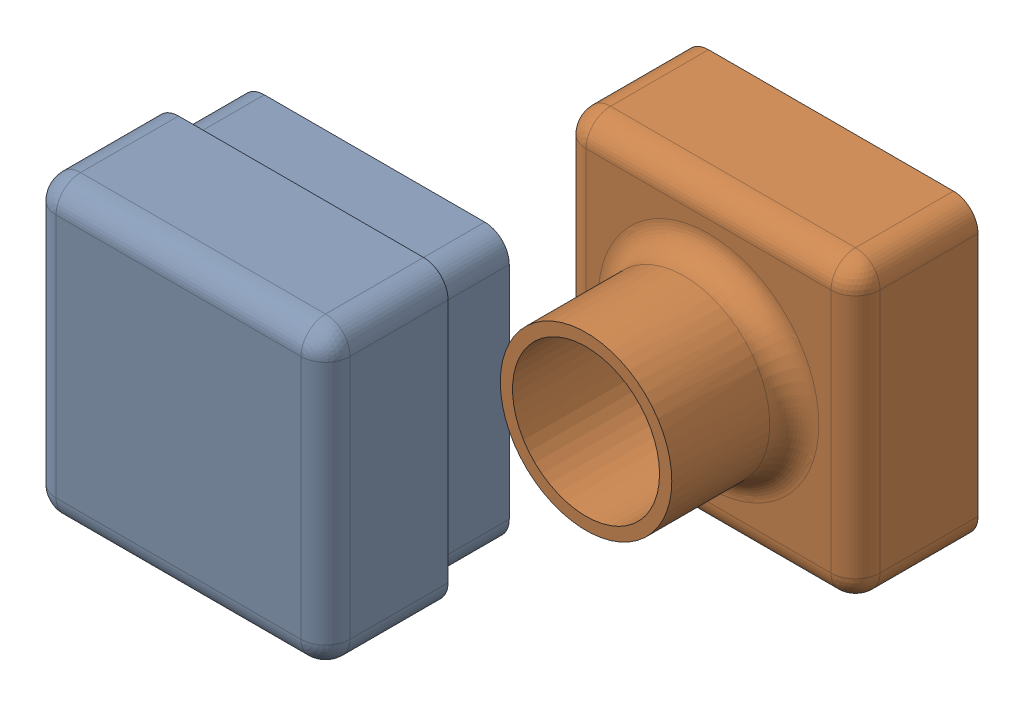
SolidWorks assembly Assem2, configuration Default. Lengths in mm.
Overall size (226.51 141.8 159.82).
2 component instances, 2 part files, 0 mates.
Components (placement in the parent):
- tas2part2-3: tas2part2 [Default] at origin size (120 120 80)
- task2part1-3: task2part1 [Default] at (106.515 21.7999 -79.8222) size (120 120 100)
